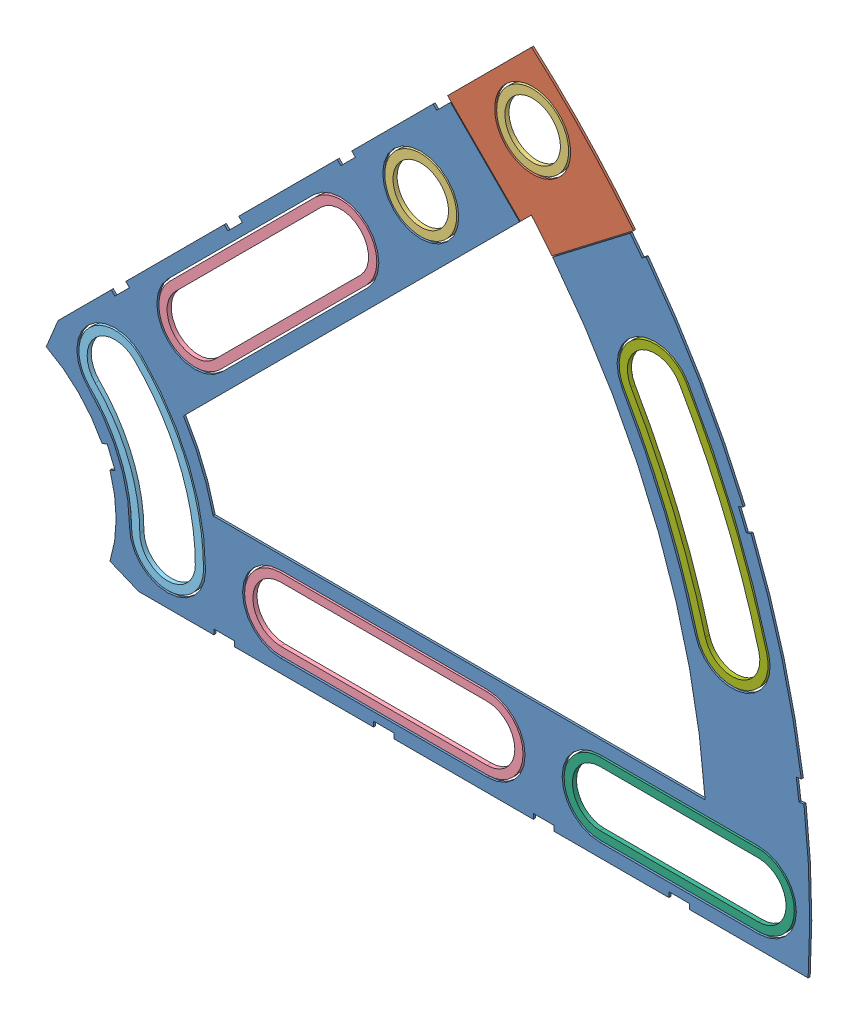
SolidWorks assembly Clover_5_Insul+Pass, configuration Default. Lengths in mm.
Overall size (96.77 82.54 0.51).
9 component instances, 7 part files, 22 mates.
Components (placement in the parent):
- Clover_5_Insul-1: Clover_5_Insul [Default] at (-12.6638 23.1054 67.6701) size (94.37 71.64 0.25)
- Clover_5_Pass-1: Clover_5_Pass [Default] at (-12.6638 23.1054 67.6701) size (22.98 21.07 0.25)
- Round_Washer-1: Round_Washer [Default] at (54.6882 90.4573 67.9241) x (1 0 0) z (0 1 0) size (8.89 0.51 8.89)
- Round_Washer-2: Round_Washer [Default] at (40.8586 76.6277 67.9241) x (1 0 0) z (0 1 0) size (8.89 0.51 8.89)
- Clover_Long_Washer-1: Clover_Long_Washer [Default] at (21.9551 57.7243 67.9241) x (0.707107 0.707107 0) z (-0.707107 0.707107 0) size (34.42 0.51 8.89)
- Clover_Long_Washer-2: Clover_Long_Washer [Default] at (36.2947 23.1054 67.9241) x (1 0 0) z (0 1 0) size (34.42 0.51 8.89)
- Curve_Inner_Washer-1: Curve_Inner_Washer [Default] at (-12.6638 23.1054 67.9241) x (0.707107 0.707107 0) z (-0.707107 0.707107 0) size (15.4 0.51 24.61)
- Clover_Med_Washer-1: Clover_Med_Washer [Default] at (72.8072 23.1054 67.9241) x (1 0 0) z (0 1 0) size (28.45 0.51 8.89)
- Clover_Outside_Washer-1: Clover_Outside_Washer [Default] at (-12.6638 23.1054 67.9241) x (0.866025 0.5 0) z (-0.5 0.866025 0) size (12.14 0.51 33.54)
Mates (geometry in assembly coordinates):
- Coincident1: coincident: plane of Clover_5_Insul-1 through (-12.6638 23.1054 67.9241) normal (0 0 1); plane of Clover_5_Pass-1 through (-12.6638 23.1054 67.9241) normal (0 0 1)
- Concentric1: concentric: cylinder of Clover_5_Insul-1 through (-12.6638 23.1054 67.9241) axis (0 0 -1) radius 101.6; cylinder of Clover_5_Pass-1 through (-12.6638 23.1054 67.9241) axis (0 0 -1) radius 101.6
- Coincident2: coincident: plane of Clover_5_Insul-1 through (54.5477 99.2971 67.9241) normal (-0.707107 0.707107 0); plane of Clover_5_Pass-1 through (54.5477 99.2971 67.9241) normal (-0.707107 0.707107 0)
- Concentric2: concentric: circle of Clover_5_Pass-1; circle of Round_Washer-1
- Coincident3: coincident: plane of Clover_5_Pass-1 through (-12.6638 23.1054 67.9241) normal (0 0 1); plane of Round_Washer-1 through (54.6882 90.4573 67.9241) normal (0 0 1)
- Concentric3: concentric: circle of Clover_5_Insul-1; circle of Round_Washer-2
- Coincident4: coincident: plane of Clover_5_Insul-1 through (-12.6638 23.1054 67.9241) normal (0 0 1); plane of Round_Washer-2 through (40.8586 76.6277 67.9241) normal (0 0 1)
- Concentric4: concentric: circle of Clover_5_Insul-1; circle of Clover_Long_Washer-1
- Concentric5: concentric: circle of Clover_5_Insul-1; circle of Clover_Long_Washer-1
- Coincident5: coincident: plane of Clover_5_Insul-1 through (-12.6638 23.1054 67.9241) normal (0 0 1); plane of Clover_Long_Washer-1 through (12.93 48.6991 67.9241) normal (0 0 1)
- Concentric6: concentric: circle of Clover_5_Insul-1; circle of Curve_Inner_Washer-1
- Concentric7: concentric: circle of Clover_5_Insul-1; circle of Curve_Inner_Washer-1
- Coincident6: coincident: plane of Clover_5_Insul-1 through (-12.6638 23.1054 67.9241) normal (0 0 1); plane of Curve_Inner_Washer-1 through (-4.806 30.9631 67.9241) normal (0 0 1)
- Concentric8: concentric: circle of Clover_5_Insul-1; circle of Clover_Long_Washer-2
- Concentric9: concentric: circle of Clover_5_Insul-1; circle of Clover_Long_Washer-2
- Coincident7: coincident: plane of Clover_5_Insul-1 through (-12.6638 23.1054 67.9241) normal (0 0 1); plane of Clover_Long_Washer-2 through (23.5312 23.1054 67.9241) normal (0 0 1)
- Concentric10: concentric: circle of Clover_5_Insul-1; circle of Clover_Med_Washer-1
- Concentric11: concentric: circle of Clover_5_Insul-1; circle of Clover_Med_Washer-1
- Coincident8: coincident: plane of Clover_5_Insul-1 through (-12.6638 23.1054 67.9241) normal (0 0 1); plane of Clover_Med_Washer-1 through (63.0282 23.1054 67.9241) normal (0 0 1)
- Concentric12: concentric: circle of Clover_5_Insul-1; circle of Clover_Outside_Washer-1
- Concentric13: concentric: circle of Clover_5_Insul-1; circle of Clover_Outside_Washer-1
- Coincident9: coincident: plane of Clover_5_Insul-1 through (-12.6638 23.1054 67.9241) normal (0 0 1); plane of Clover_Outside_Washer-1 through (28.5807 46.9179 67.9241) normal (0 0 1)
